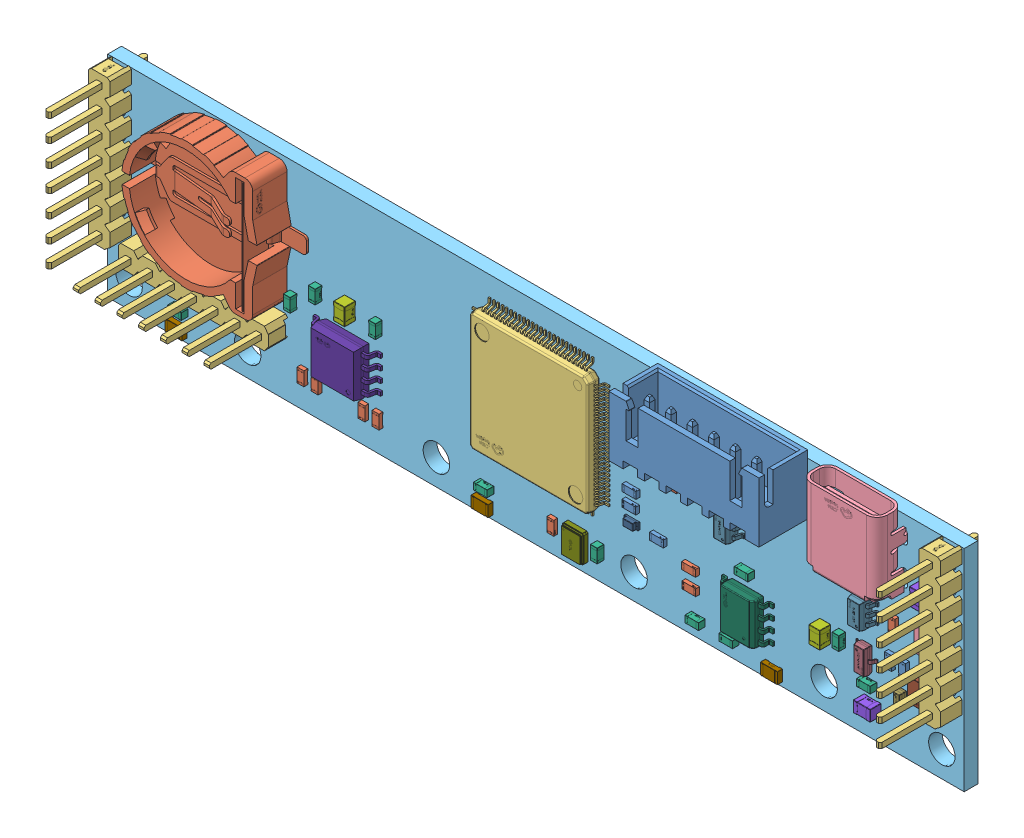
SolidWorks assembly 3D_PCB_PCB_ampere_clock-copy_2024-03-30_2024-03-30, configuration 默认. Lengths in mm.
Overall size (108.1 70.34 12).
242 component instances, 25 part files, 0 mates.
Components (placement in the parent):
- 3D_PCB_PCB_ampere_clock-copy_2024-03-30_2024-03-30.step-1: 3D_PCB_PCB_ampere_clock-copy_2024-03-30_2024-03-30.step [默认] at origin size (108.1 70.34 12)
  - R4.step-1: R4.step [默认] at (63.4112 92.2809 0) x (1 0 0) z (0 0 -1) size (3.2 1.6 0.56)
    - footprint_4e6b.step-1: footprint_4e6b.step [默认] at origin size (3.2 1.6 0.56)
      - COMPOUND-4.step-1: COMPOUND-4.step [默认] at origin size (3.2 1.6 0.56)
  - R5.step-1: R5.step [默认] at (56.6421 92.2631 0) x (1 0 0) z (0 0 -1) size (1.62 0.81 0.45)
    - footprint_4858.step-1: footprint_4858.step [默认] at origin size (1.62 0.81 0.45)
      - COMPOUND.step-1: COMPOUND.step [默认] at origin size (1.62 0.81 0.45)
  - R6.step-1: R6.step [默认] at (18.3566 88.2525 0) x (1 0 0) z (0 0 -1) size (1.62 0.81 0.45)
    - footprint_4858.step-1: footprint_4858.step [默认] at origin size (1.62 0.81 0.45)
      - COMPOUND.step-1: COMPOUND.step [默认] at origin size (1.62 0.81 0.45)
  - R28.step-1: R28.step [默认] at (25.1029 88.2525 0) x (1 0 0) z (0 0 -1) size (1.62 0.81 0.45)
    - footprint_94f4.step-1: footprint_94f4.step [默认] at origin size (1.62 0.81 0.45)
      - COMPOUND.step-1: COMPOUND.step [默认] at origin size (1.62 0.81 0.45)
  - R29.step-1: R29.step [默认] at (11.6764 88.2525 0) x (1 0 0) z (0 0 -1) size (1.62 0.81 0.45)
    - footprint_94f4.step-1: footprint_94f4.step [默认] at origin size (1.62 0.81 0.45)
      - COMPOUND.step-1: COMPOUND.step [默认] at origin size (1.62 0.81 0.45)
  - R25.step-1: R25.step [默认] at (88.0645 92.2936 0) x (-1 0 0) z (0 0 -1) size (2 1.3 0.61)
    - footprint_7ba0.step-1: footprint_7ba0.step [默认] at origin size (2 1.3 0.61)
      - COMPOUND-1.step-1: COMPOUND-1.step [默认] at origin size (2 1.3 0.61)
  - R26.step-1: R26.step [默认] at (101.8669 92.2936 0) x (-1 0 0) z (0 0 -1) size (1.62 0.81 0.45)
    - footprint_4858.step-1: footprint_4858.step [默认] at origin size (1.62 0.81 0.45)
      - COMPOUND.step-1: COMPOUND.step [默认] at origin size (1.62 0.81 0.45)
  - R27.step-1: R27.step [默认] at (95.5474 92.2936 0) x (-1 0 0) z (0 0 -1) size (1.62 0.81 0.45)
    - footprint_94f4.step-1: footprint_94f4.step [默认] at origin size (1.62 0.81 0.45)
      - COMPOUND.step-1: COMPOUND.step [默认] at origin size (1.62 0.81 0.45)
  - R7.step-1: R7.step [默认] at (67.7318 79.8349 1.6001) x (-1 0 0) z (0 0 1) size (1.62 0.81 0.45)
    - footprint_4858.step-1: footprint_4858.step [默认] at origin size (1.62 0.81 0.45)
      - COMPOUND.step-1: COMPOUND.step [默认] at origin size (1.62 0.81 0.45)
  - R9.step-1: R9.step [默认] at (67.7064 78.2499 1.6001) x (-1 0 0) z (0 0 1) size (1.62 0.81 0.45)
    - footprint_4858.step-1: footprint_4858.step [默认] at origin size (1.62 0.81 0.45)
      - COMPOUND.step-1: COMPOUND.step [默认] at origin size (1.62 0.81 0.45)
  - R21.step-1: R21.step [默认] at (98.3668 81.6205 1.6001) x (0 1 0) z (0 0 1) size (1.62 0.81 0.45)
    - footprint_6a04.step-1: footprint_6a04.step [默认] at origin size (1.62 0.81 0.45)
      - COMPOUND-0.step-1: COMPOUND-0.step [默认] at origin size (1.62 0.81 0.45)
  - R1.step-1: R1.step [默认] at (97.9578 77.7597 1.6001) x (0 -1 0) z (0 0 1) size (1.62 0.81 0.45)
    - footprint_4858.step-1: footprint_4858.step [默认] at origin size (1.62 0.81 0.45)
      - COMPOUND.step-1: COMPOUND.step [默认] at origin size (1.62 0.81 0.45)
  - R2.step-1: R2.step [默认] at (99.6165 77.7597 1.6001) x (0 1 0) z (0 0 1) size (1.62 0.81 0.45)
    - footprint_4858.step-1: footprint_4858.step [默认] at origin size (1.62 0.81 0.45)
      - COMPOUND.step-1: COMPOUND.step [默认] at origin size (1.62 0.81 0.45)
  - R8.step-1: R8.step [默认] at (70.9271 76.5253 1.6001) x (-1 0 0) z (0 0 1) size (1.62 0.81 0.45)
    - footprint_4858.step-1: footprint_4858.step [默认] at origin size (1.62 0.81 0.45)
      - COMPOUND.step-1: COMPOUND.step [默认] at origin size (1.62 0.81 0.45)
  - R11.step-1: R11.step [默认] at (72.4663 84.9301 1.6001) x (-1 0 0) z (0 0 1) size (1.62 0.81 0.45)
    - footprint_6a04.step-1: footprint_6a04.step [默认] at origin size (1.62 0.81 0.45)
      - COMPOUND-0.step-1: COMPOUND-0.step [默认] at origin size (1.62 0.81 0.45)
  - R12.step-1: R12.step [默认] at (58.5547 71.7247 1.6001) x (0 1 0) z (0 0 1) size (1.62 0.81 0.45)
    - footprint_6a04.step-1: footprint_6a04.step [默认] at origin size (1.62 0.81 0.45)
      - COMPOUND-0.step-1: COMPOUND-0.step [默认] at origin size (1.62 0.81 0.45)
  - R13.step-1: R13.step [默认] at (31.0287 72.253 1.6001) x (0 -1 0) z (0 0 1) size (1.62 0.81 0.45)
    - footprint_6a04.step-1: footprint_6a04.step [默认] at origin size (1.62 0.81 0.45)
      - COMPOUND-0.step-1: COMPOUND-0.step [默认] at origin size (1.62 0.81 0.45)
  - R14.step-1: R14.step [默认] at (29.3777 72.253 1.6001) x (0 -1 0) z (0 0 1) size (1.62 0.81 0.45)
    - footprint_6a04.step-1: footprint_6a04.step [默认] at origin size (1.62 0.81 0.45)
      - COMPOUND-0.step-1: COMPOUND-0.step [默认] at origin size (1.62 0.81 0.45)
  - R15.step-1: R15.step [默认] at (36.4897 72.253 1.6001) x (0 -1 0) z (0 0 1) size (1.62 0.81 0.45)
    - footprint_6a04.step-1: footprint_6a04.step [默认] at origin size (1.62 0.81 0.45)
      - COMPOUND-0.step-1: COMPOUND-0.step [默认] at origin size (1.62 0.81 0.45)
  - R16.step-1: R16.step [默认] at (38.1407 72.253 1.6001) x (0 -1 0) z (0 0 1) size (1.62 0.81 0.45)
    - footprint_6a04.step-1: footprint_6a04.step [默认] at origin size (1.62 0.81 0.45)
      - COMPOUND-0.step-1: COMPOUND-0.step [默认] at origin size (1.62 0.81 0.45)
  - R23.step-1: R23.step [默认] at (74.7117 73.4976 1.6001) x (-1 0 0) z (0 0 1) size (1.62 0.81 0.45)
    - footprint_6a04.step-1: footprint_6a04.step [默认] at origin size (1.62 0.81 0.45)
      - COMPOUND-0.step-1: COMPOUND-0.step [默认] at origin size (1.62 0.81 0.45)
  - R24.step-1: R24.step [默认] at (74.6761 75.4382 1.6001) x (-1 0 0) z (0 0 1) size (1.62 0.81 0.45)
    - footprint_6a04.step-1: footprint_6a04.step [默认] at origin size (1.62 0.81 0.45)
      - COMPOUND-0.step-1: COMPOUND-0.step [默认] at origin size (1.62 0.81 0.45)
  - R22.step-1: R22.step [默认] at (89.2558 84.0742 1.6001) x (0 1 0) z (0 0 1) size (1.62 0.81 0.45)
    - footprint_6a04.step-1: footprint_6a04.step [默认] at origin size (1.62 0.81 0.45)
      - COMPOUND-0.step-1: COMPOUND-0.step [默认] at origin size (1.62 0.81 0.45)
  - R20.step-1: R20.step [默认] at (72.4384 82.7686 1.6001) x (-1 0 0) z (0 0 1) size (1.62 0.81 0.45)
    - footprint_6a04.step-1: footprint_6a04.step [默认] at origin size (1.62 0.81 0.45)
      - COMPOUND-0.step-1: COMPOUND-0.step [默认] at origin size (1.62 0.81 0.45)
  - R3.step-1: R3.step [默认] at (50.4775 92.2631 0) x (-1 0 0) z (0 0 -1) size (1.62 0.81 0.45)
    - footprint_4858.step-1: footprint_4858.step [默认] at origin size (1.62 0.81 0.45)
      - COMPOUND.step-1: COMPOUND.step [默认] at origin size (1.62 0.81 0.45)
  - H4.step-1: H4.step [默认] at (18.9484 76.0732 1.6001) x (-1 0 0) z (0 0 1) size (15.25 2.5 11.5)
    - footprint_8506.step-1: footprint_8506.step [默认] at origin size (15.25 2.5 11.5)
      - SOLID.step-1: SOLID.step [默认] at origin size (15.25 2.5 11.5)
  - F1.step-1: F1.step [默认] at (101.9964 81.9634 1.6001) x (0 -1 0) z (0 0 1) size (3.2 1.7 0.6)
    - footprint_5ef7.step-1: footprint_5ef7.step [默认] at origin size (3.2 1.7 0.6)
      - SOLID-1.step-1: SOLID-1.step [默认] at origin size (3.2 1.7 0.6)
  - C9.step-1: C9.step [默认] at (52.3825 86.698 0) x (-0.707107 0.707107 0) z (0 0 -1) size (1.6 0.8 0.8)
    - footprint_151d.step-1: footprint_151d.step [默认] at origin size (1.6 0.8 0.8)
      - SOLID-2.step-1: SOLID-2.step [默认] at origin size (1.6 0.8 0.8)
  - C33.step-1: C33.step [默认] at (101.9761 86.2281 0) x (0 -1 0) z (0 0 -1) size (1.6 0.8 0.8)
    - footprint_eb00.step-1: footprint_eb00.step [默认] at origin size (1.6 0.8 0.8)
      - SOLID-3.step-1: SOLID-3.step [默认] at origin size (1.6 0.8 0.8)
  - C14.step-1: C14.step [默认] at (52.474 80.6325 0) x (-0.707107 -0.707107 0) z (0 0 -1) size (1.6 0.8 0.8)
    - footprint_151d.step-1: footprint_151d.step [默认] at origin size (1.6 0.8 0.8)
      - SOLID-2.step-1: SOLID-2.step [默认] at origin size (1.6 0.8 0.8)
  - C6.step-1: C6.step [默认] at (61.6586 79.6977 0) x (0.707107 -0.707107 0) z (0 0 -1) size (1.6 0.8 0.8)
    - footprint_151d.step-1: footprint_151d.step [默认] at origin size (1.6 0.8 0.8)
      - SOLID-2.step-1: SOLID-2.step [默认] at origin size (1.6 0.8 0.8)
  - C7.step-1: C7.step [默认] at (53.65 87.9223 0) x (-0.707107 0.707107 0) z (0 0 -1) size (1.6 0.8 0.8)
    - footprint_151d.step-1: footprint_151d.step [默认] at origin size (1.6 0.8 0.8)
      - SOLID-2.step-1: SOLID-2.step [默认] at origin size (1.6 0.8 0.8)
  - C8.step-1: C8.step [默认] at (55.1003 78.0874 0) x (-0.707107 -0.707107 0) z (0 0 -1) size (1.6 0.8 0.8)
    - footprint_151d.step-1: footprint_151d.step [默认] at origin size (1.6 0.8 0.8)
      - SOLID-2.step-1: SOLID-2.step [默认] at origin size (1.6 0.8 0.8)
  - C11.step-1: C11.step [默认] at (61.5672 85.0521 0) x (0.707107 0.707107 0) z (0 0 -1) size (1.6 0.8 0.8)
    - footprint_151d.step-1: footprint_151d.step [默认] at origin size (1.6 0.8 0.8)
      - SOLID-2.step-1: SOLID-2.step [默认] at origin size (1.6 0.8 0.8)
  - C12.step-1: C12.step [默认] at (58.9942 87.5413 0) x (0.707107 0.707107 0) z (0 0 -1) size (1.6 0.8 0.8)
    - footprint_151d.step-1: footprint_151d.step [默认] at origin size (1.6 0.8 0.8)
      - SOLID-2.step-1: SOLID-2.step [默认] at origin size (1.6 0.8 0.8)
  - C13.step-1: C13.step [默认] at (60.2769 86.3094 0) x (0.707107 0.707107 0) z (0 0 -1) size (1.6 0.8 0.8)
    - footprint_151d.step-1: footprint_151d.step [默认] at origin size (1.6 0.8 0.8)
      - SOLID-2.step-1: SOLID-2.step [默认] at origin size (1.6 0.8 0.8)
  - C15.step-1: C15.step [默认] at (53.7694 79.3574 0) x (-0.707107 -0.707107 0) z (0 0 -1) size (1.6 0.8 0.8)
    - footprint_151d.step-1: footprint_151d.step [默认] at origin size (1.6 0.8 0.8)
      - SOLID-2.step-1: SOLID-2.step [默认] at origin size (1.6 0.8 0.8)
  - C3.step-1: C3.step [默认] at (95.4255 74.1631 1.6001) size (1.6 0.8 0.8)
    - footprint_eb00.step-1: footprint_eb00.step [默认] at origin size (1.6 0.8 0.8)
      - SOLID-3.step-1: SOLID-3.step [默认] at origin size (1.6 0.8 0.8)
  - C5.step-1: C5.step [默认] at (92.1717 77.0307 1.6001) x (0 -1 0) z (0 0 1) size (1.6 0.8 0.8)
    - footprint_eb00.step-1: footprint_eb00.step [默认] at origin size (1.6 0.8 0.8)
      - SOLID-3.step-1: SOLID-3.step [默认] at origin size (1.6 0.8 0.8)
  - C20.step-1: C20.step [默认] at (63.9675 71.7907 1.6001) x (0 1 0) z (0 0 1) size (1.6 0.8 0.8)
    - footprint_eb00.step-1: footprint_eb00.step [默认] at origin size (1.6 0.8 0.8)
      - SOLID-3.step-1: SOLID-3.step [默认] at origin size (1.6 0.8 0.8)
  - C21.step-1: C21.step [默认] at (31.0389 81.5037 1.6001) x (0 -1 0) z (0 0 1) size (1.6 0.8 0.8)
    - footprint_eb00.step-1: footprint_eb00.step [默认] at origin size (1.6 0.8 0.8)
      - SOLID-3.step-1: SOLID-3.step [默认] at origin size (1.6 0.8 0.8)
  - C22.step-1: C22.step [默认] at (38.0798 81.5215 1.6001) x (0 1 0) z (0 0 1) size (1.6 0.8 0.8)
    - footprint_eb00.step-1: footprint_eb00.step [默认] at origin size (1.6 0.8 0.8)
      - SOLID-3.step-1: SOLID-3.step [默认] at origin size (1.6 0.8 0.8)
  - C24.step-1: C24.step [默认] at (28.1204 79.205 1.6001) x (0 1 0) z (0 0 1) size (1.6 0.8 0.8)
    - footprint_eb00.step-1: footprint_eb00.step [默认] at origin size (1.6 0.8 0.8)
      - SOLID-3.step-1: SOLID-3.step [默认] at origin size (1.6 0.8 0.8)
  - C29.step-1: C29.step [默认] at (15.014 71.7221 1.6001) size (1.6 0.8 0.8)
    - footprint_eb00.step-1: footprint_eb00.step [默认] at origin size (1.6 0.8 0.8)
      - SOLID-3.step-1: SOLID-3.step [默认] at origin size (1.6 0.8 0.8)
  - C30.step-1: C30.step [默认] at (50.7112 71.6535 1.6001) size (1.6 0.8 0.8)
    - footprint_eb00.step-1: footprint_eb00.step [默认] at origin size (1.6 0.8 0.8)
      - SOLID-3.step-1: SOLID-3.step [默认] at origin size (1.6 0.8 0.8)
  - C31.step-1: C31.step [默认] at (75.3924 70.5639 1.6001) size (1.6 0.8 0.8)
    - footprint_eb00.step-1: footprint_eb00.step [默认] at origin size (1.6 0.8 0.8)
      - SOLID-3.step-1: SOLID-3.step [默认] at origin size (1.6 0.8 0.8)
  - C34.step-1: C34.step [默认] at (79.3498 70.7061 1.6001) x (-1 0 0) z (0 0 1) size (1.6 0.8 0.8)
    - footprint_eb00.step-1: footprint_eb00.step [默认] at origin size (1.6 0.8 0.8)
      - SOLID-3.step-1: SOLID-3.step [默认] at origin size (1.6 0.8 0.8)
  - C35.step-1: C35.step [默认] at (81.1532 78.3592 1.6001) x (-1 0 0) z (0 0 1) size (1.6 0.8 0.8)
    - footprint_eb00.step-1: footprint_eb00.step [默认] at origin size (1.6 0.8 0.8)
      - SOLID-3.step-1: SOLID-3.step [默认] at origin size (1.6 0.8 0.8)
  - C10.step-1: C10.step [默认] at (60.0356 78.1128 0) x (0.707107 -0.707107 0) z (0 0 -1) size (1.6 0.8 0.8)
    - footprint_151d.step-1: footprint_151d.step [默认] at origin size (1.6 0.8 0.8)
      - SOLID-2.step-1: SOLID-2.step [默认] at origin size (1.6 0.8 0.8)
  - C4.step-1: C4.step [默认] at (90.2032 76.7463 1.6001) x (0 -1 0) z (0 0 1) size (2 1.3 1.3)
    - footprint_5973.step-1: footprint_5973.step [默认] at origin size (2 1.3 1.3)
      - SOLID-4.step-1: SOLID-4.step [默认] at origin size (2 1.3 1.3)
  - C23.step-1: C23.step [默认] at (34.7269 81.6993 1.6001) x (0 -1 0) z (0 0 1) size (2 1.3 1.3)
    - footprint_5973.step-1: footprint_5973.step [默认] at origin size (2 1.3 1.3)
      - SOLID-4.step-1: SOLID-4.step [默认] at origin size (2 1.3 1.3)
  - C32.step-1: C32.step [默认] at (101.938 86.4415 1.6001) x (0 -1 0) z (0 0 1) size (2 1.3 1.3)
    - footprint_c85c.step-1: footprint_c85c.step [默认] at origin size (2 1.3 1.3)
      - SOLID-5.step-1: SOLID-5.step [默认] at origin size (2 1.3 1.3)
  - C2.step-1: C2.step [默认] at (95.7379 72.0574 1.6001) size (2 1.3 1.3)
    - footprint_c85c.step-1: footprint_c85c.step [默认] at origin size (2 1.3 1.3)
      - SOLID-5.step-1: SOLID-5.step [默认] at origin size (2 1.3 1.3)
  - R18.step-1: R18.step [默认] at (50.4343 69.7612 1.6001) x (-1 0 0) z (0 0 1) size (8.21 6 8.4)
    - footprint_78d0.step-1: footprint_78d0.step [默认] at origin size (8.21 6 8.4)
      - COMPOUND-6.step-1: COMPOUND-6.step [默认] at origin size (8.21 6 8.4)
  - R19.step-1: R19.step [默认] at (84.2088 69.7612 1.6001) size (8.21 6 8.4)
    - footprint_78d0.step-1: footprint_78d0.step [默认] at origin size (8.21 6 8.4)
      - COMPOUND-6.step-1: COMPOUND-6.step [默认] at origin size (8.21 6 8.4)
  - R17.step-1: R17.step [默认] at (14.6965 69.7612 1.6001) x (-1 0 0) z (0 0 1) size (8.21 6 8.4)
    - footprint_78d0.step-1: footprint_78d0.step [默认] at origin size (8.21 6 8.4)
      - COMPOUND-6.step-1: COMPOUND-6.step [默认] at origin size (8.21 6 8.4)
  - LED3.step-1: LED3.step [默认] at (67.7292 76.5405 1.6001) x (-1 0 0) z (0 0 1) size (1.62 0.81 0.61)
    - footprint_18a6.step-1: footprint_18a6.step [默认] at origin size (1.62 0.81 0.61)
      - COMPOUND-7.step-1: COMPOUND-7.step [默认] at origin size (1.62 0.81 0.61)
  - U2.step-1: U2.step [默认] at (101.9761 77.1044 1.6001) x (0 1 0) z (0 0 1) size (3.85 1.7 1.45)
    - footprint_1c63.step-1: footprint_1c63.step [默认] at origin size (3.85 1.7 1.45)
      - SOLID-8.step-1: SOLID-8.step [默认] at origin size (3.85 1.7 1.45)
  - U4.step-1: U4.step [默认] at (99.6063 74.9378 1.6001) x (-1 0 0) z (0 0 1) size (99.98 24.59 1.6)
    - footprint_04b7.step-1: footprint_04b7.step [默认] at origin size (99.98 24.59 1.6)
      - COMPOUND-9.step-1: COMPOUND-9.step [默认] at origin size (99.98 24.59 1.6)
  - U5.step-1: U5.step [默认] at (95.1334 76.7259 1.6001) x (-1 0 0) z (0 0 1) size (2.5 2.89 1.05)
    - footprint_f658.step-1: footprint_f658.step [默认] at origin size (2.5 2.89 1.05)
      - COMPOUND-10.step-1: COMPOUND-10.step [默认] at origin size (2.5 2.89 1.05)
  - H2.step-1: H2.step [默认] at (104.9022 84.511 1.6001) x (0 1 0) z (0 0 1) size (15.25 2.5 11.5)
    - footprint_f8ae.step-1: footprint_f8ae.step [默认] at origin size (15.25 2.5 11.5)
      - SOLID.step-1: SOLID.step [默认] at origin size (15.25 2.5 11.5)
  - H1.step-1: H1.step [默认] at (7.9477 84.511 1.6001) x (0 1 0) z (0 0 1) size (15.25 2.5 11.5)
    - footprint_f8ae.step-1: footprint_f8ae.step [默认] at origin size (15.25 2.5 11.5)
      - SOLID.step-1: SOLID.step [默认] at origin size (15.25 2.5 11.5)
  - D2.step-1: D2.step [默认] at (95.108 81.6535 1.6001) x (0 1 0) z (0 0 1) size (2.88 2.79 1.64)
    - footprint_17c6.step-1: footprint_17c6.step [默认] at origin size (2.88 2.79 1.64)
      - COMPOUND-12.step-1: COMPOUND-12.step [默认] at origin size (2.88 2.79 1.64)
  - D1.step-1: D1.step [默认] at (79.4844 82.6289 1.6001) x (0 1 0) z (0 0 1) size (2.88 2.79 1.64)
    - footprint_17c6.step-1: footprint_17c6.step [默认] at origin size (2.88 2.79 1.64)
      - COMPOUND-12.step-1: COMPOUND-12.step [默认] at origin size (2.88 2.79 1.64)
  - U9.step-1: U9.step [默认] at (81.2802 74.4221 1.6001) x (0 1 0) z (0 0 1) size (4.9 6 1.5)
    - footprint_caf9.step-1: footprint_caf9.step [默认] at origin size (4.9 6 1.5)
      - COMPOUND-13.step-1: COMPOUND-13.step [默认] at origin size (4.9 6 1.5)
  - X1.step-1: X1.step [默认] at (61.2776 71.3589 1.6001) x (0 -1 0) z (0 0 1) size (3.2 2.5 0.81)
    - footprint_59ac.step-1: footprint_59ac.step [默认] at origin size (3.2 2.5 0.81)
      - SOLID-14.step-1: SOLID-14.step [默认] at origin size (3.2 2.5 0.81)
  - U7.step-1: U7.step [默认] at (34.5822 76.8733 1.6001) x (0 1 0) z (0 0 1) size (5.23 7.9 1.95)
    - footprint_6933.step-1: footprint_6933.step [默认] at origin size (5.23 7.9 1.95)
      - COMPOUND-15.step-1: COMPOUND-15.step [默认] at origin size (5.23 7.9 1.95)
  - LED2.step-1: LED2.step [默认] at (63.6881 90.3531 0) x (-1 0 0) z (0 0 -1) size (2.02 1.26 1.01)
    - footprint_bd74.step-1: footprint_bd74.step [默认] at origin size (2.02 1.26 1.01)
      - COMPOUND-16.step-1: COMPOUND-16.step [默认] at origin size (2.02 1.26 1.01)
  - LED4.step-1: LED4.step [默认] at (11.966 90.3531 0) x (-1 0 0) z (0 0 -1) size (2.02 1.26 1.01)
    - footprint_bd74.step-1: footprint_bd74.step [默认] at origin size (2.02 1.26 1.01)
      - COMPOUND-16.step-1: COMPOUND-16.step [默认] at origin size (2.02 1.26 1.01)
  - LED5.step-1: LED5.step [默认] at (25.3924 90.3505 0) x (-1 0 0) z (0 0 -1) size (2.02 1.26 1.01)
    - footprint_bd74.step-1: footprint_bd74.step [默认] at origin size (2.02 1.26 1.01)
      - COMPOUND-16.step-1: COMPOUND-16.step [默认] at origin size (2.02 1.26 1.01)
  - LED6.step-1: LED6.step [默认] at (101.8847 90.3353 0) x (1 0 0) z (0 0 -1) size (2.02 1.26 1.01)
    - footprint_bd74.step-1: footprint_bd74.step [默认] at origin size (2.02 1.26 1.01)
      - COMPOUND-16.step-1: COMPOUND-16.step [默认] at origin size (2.02 1.26 1.01)
  - LED7.step-1: LED7.step [默认] at (95.2731 90.3556 0) x (1 0 0) z (0 0 -1) size (2.02 1.26 1.01)
    - footprint_bd74.step-1: footprint_bd74.step [默认] at origin size (2.02 1.26 1.01)
      - COMPOUND-16.step-1: COMPOUND-16.step [默认] at origin size (2.02 1.26 1.01)
  - LED8.step-1: LED8.step [默认] at (56.9774 90.3531 0) x (-1 0 0) z (0 0 -1) size (2.02 1.26 1.01)
    - footprint_bd74.step-1: footprint_bd74.step [默认] at origin size (2.02 1.26 1.01)
      - COMPOUND-16.step-1: COMPOUND-16.step [默认] at origin size (2.02 1.26 1.01)
  - LED9.step-1: LED9.step [默认] at (18.6309 90.3505 0) x (-1 0 0) z (0 0 -1) size (2.02 1.26 1.01)
    - footprint_bd74.step-1: footprint_bd74.step [默认] at origin size (2.02 1.26 1.01)
      - COMPOUND-16.step-1: COMPOUND-16.step [默认] at origin size (2.02 1.26 1.01)
  - LED11.step-1: LED11.step [默认] at (88.3592 90.3505 0) x (1 0 0) z (0 0 -1) size (2.02 1.26 1.01)
    - footprint_bd74.step-1: footprint_bd74.step [默认] at origin size (2.02 1.26 1.01)
      - COMPOUND-16.step-1: COMPOUND-16.step [默认] at origin size (2.02 1.26 1.01)
  - LED1.step-1: LED1.step [默认] at (50.2057 90.3531 0) x (1 0 0) z (0 0 -1) size (2.02 1.26 1.01)
    - footprint_bd74.step-1: footprint_bd74.step [默认] at origin size (2.02 1.26 1.01)
      - COMPOUND-16.step-1: COMPOUND-16.step [默认] at origin size (2.02 1.26 1.01)
  - CN3.step-1: CN3.step [默认] at (79.4954 87.1806 1.6001) x (-1 0 0) z (0 0 1) size (17.5 7.32 9.1)
    - footprint_c1a5.step-1: footprint_c1a5.step [默认] at origin size (17.5 7.32 9.1)
      - COMPOUND-17.step-1: COMPOUND-17.step [默认] at origin size (17.5 7.32 9.1)
  - B1.step-1: B1.step [默认] at (19.5733 85.6236 1.6001) x (-1 0 0) z (0 0 1) size (19.76 14.9 4.9)
    - footprint_9df6.step-1: footprint_9df6.step [默认] at origin size (19.76 14.9 4.9)
      - SOLID-18.step-1: SOLID-18.step [默认] at origin size (19.76 14.9 4.9)
  - U1.step-1: U1.step [默认] at (57.079 82.9134 1.6001) x (-1 0 0) z (0 0 1) size (16 16 1.5)
    - footprint_d888.step-1: footprint_d888.step [默认] at origin size (16 16 1.5)
      - SOLID-19.step-1: SOLID-19.step [默认] at origin size (16 16 1.5)
  - USB1.step-1: USB1.step [默认] at (95.1207 88.5589 1.6001) x (-1 0 0) z (0 0 1) size (8.94 8.97 4.36)
    - footprint_c951.step-1: footprint_c951.step [默认] at origin size (8.94 8.97 4.36)
      - COMPOUND-20.step-1: COMPOUND-20.step [默认] at origin size (8.94 8.97 4.36)
  - COMPOUND-21.step-1: COMPOUND-21.step [默认] at origin size (99.98 24.59 1.6)
